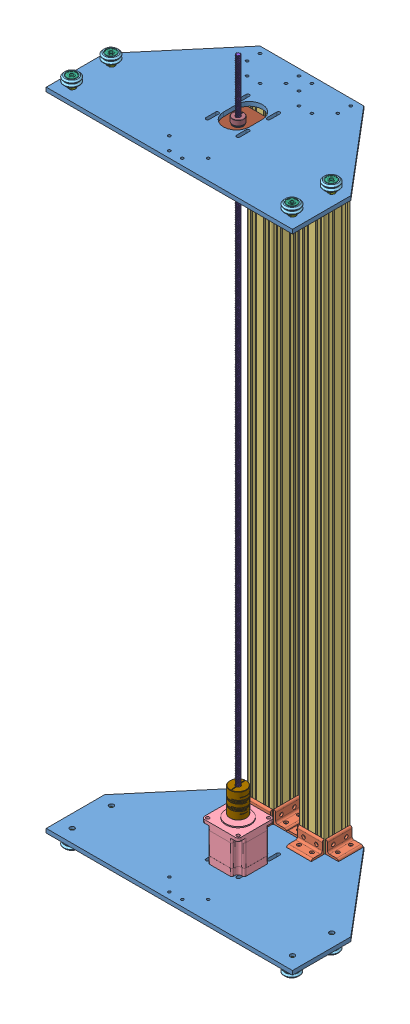
SolidWorks assembly X tray assembly, configuration Default. Lengths in mm.
Overall size (380 1106.3 220).
63 component instances, 13 part files, 91 mates.
Components (placement in the parent):
- X tray brackets-1: X tray brackets [Default] at (62.6987 262.9212 289.5469) size (380 6.35 220)
- 5537T939-1: 5537T939 [5537T939] at (202.6987 269.2712 309.5469) size (20 20 38)
- 5537T939-2: 5537T939 [5537T939] at (102.6987 269.2712 329.5469) x (0 0 1) z (-1 0 0) size (20 20 38)
- 5537T939-3: 5537T939 [5537T939] at (82.6987 269.2712 309.5469) x (-1 0 0) z (0 0 -1) size (20 20 38)
- V-Slot 40x40 Linear Rail X tray-1: V-Slot 40x40 Linear Rail X tray [Default] at (182.6987 269.2712 309.5469) x (1 0 0) z (0 1 0) size (40 40 984.25)
- V-Slot 40x40 Linear Rail X tray-2: V-Slot 40x40 Linear Rail X tray [Default] at (102.6987 269.2712 309.5469) x (1 0 0) z (0 1 0) size (40 40 984.25)
- X tray brackets-2: X tray brackets [Default] at (62.6987 1253.5212 289.5469) size (380 6.35 220)
- 5537T939-4: 5537T939 [5537T939] at (202.6987 1253.5212 309.5469) x (0 -1 0) z (0 0 1) size (20 20 38)
- 5537T939-5: 5537T939 [5537T939] at (82.6987 1253.5212 309.5469) x (-1 0 0) z (0 0 1) size (20 20 38)
- 5537T939-6: 5537T939 [5537T939] at (102.6987 1253.5212 329.5469) x (0 0 1) z (1 0 0) size (20 20 38)
- Nema 23 Stepper Motor-1: Nema 23 Stepper Motor [Default] at (142.6987 325.2712 403.4269) x (1 0 0) z (0 1 0) size (56.4 56.4 76.6)
- V wheel bearing assembly-1: V wheel bearing assembly [Default] at (298.8349 1279.1117 411.6739) x (0 -1 0) z (0 0 1) size (11 23.9 23.9)
  - Delrin V Wheel-2: Delrin V Wheel [Default] at (7.7405 13.8638 18.023) size (10.23 23.9 23.9)
  - Ball Bearing 5 x 16 x 5-2: Ball Bearing 5 x 16 x 5 [Default] at (10.7405 13.8638 18.023) size (5 16 16)
  - Ball Bearing 5 x 16 x 5-3: Ball Bearing 5 x 16 x 5 [Default] at (4.7405 13.8638 18.023) size (5 16 16)
- V wheel bearing assembly-2: V wheel bearing assembly [Default] at (298.8349 1279.1117 472.3139) x (0 -1 0) z (0 0 1) size (11 23.9 23.9)
  - Delrin V Wheel-2: Delrin V Wheel [Default] at (7.7405 13.8638 18.023) size (10.23 23.9 23.9)
  - Ball Bearing 5 x 16 x 5-2: Ball Bearing 5 x 16 x 5 [Default] at (10.7405 13.8638 18.023) size (5 16 16)
  - Ball Bearing 5 x 16 x 5-3: Ball Bearing 5 x 16 x 5 [Default] at (4.7405 13.8638 18.023) size (5 16 16)
- Eccentric Spacer 6mm-1: Eccentric Spacer 6mm [Default] at (312.6987 1259.8712 428.9069) size (11.55 8.5 10)
- Eccentric Spacer 6mm-2: Eccentric Spacer 6mm [Default] at (312.6987 1259.8712 489.5469) size (11.55 8.5 10)
- Eccentric Spacer 6mm-3: Eccentric Spacer 6mm [Default] at (-27.3013 1259.8712 428.9069) size (11.55 8.5 10)
- Eccentric Spacer 6mm-4: Eccentric Spacer 6mm [Default] at (-27.3013 1259.8712 489.5469) size (11.55 8.5 10)
- Eccentric Spacer 6mm-5: Eccentric Spacer 6mm [Default] at (-27.3013 262.9212 428.9069) x (-0.837169 0 -0.546944) z (-0.546944 0 0.837169) size (11.55 8.5 10)
- Eccentric Spacer 6mm-6: Eccentric Spacer 6mm [Default] at (-27.3013 262.9212 489.5469) x (-0.227691 0 -0.973733) z (-0.973733 0 0.227691) size (11.55 8.5 10)
- Eccentric Spacer 6mm-7: Eccentric Spacer 6mm [Default] at (312.6987 262.9212 428.9069) x (-0.311398 0 -0.95028) z (-0.95028 0 0.311398) size (11.55 8.5 10)
- Eccentric Spacer 6mm-8: Eccentric Spacer 6mm [Default] at (312.6987 262.9212 489.5469) x (-0.837169 0 -0.546944) z (-0.546944 0 0.837169) size (11.55 8.5 10)
- V wheel bearing assembly-3: V wheel bearing assembly [Default] at (-41.1651 1279.1117 411.6739) x (0 -1 0) z (0 0 1) size (11 23.9 23.9)
  - Delrin V Wheel-2: Delrin V Wheel [Default] at (7.7405 13.8638 18.023) size (10.23 23.9 23.9)
  - Ball Bearing 5 x 16 x 5-2: Ball Bearing 5 x 16 x 5 [Default] at (10.7405 13.8638 18.023) size (5 16 16)
  - Ball Bearing 5 x 16 x 5-3: Ball Bearing 5 x 16 x 5 [Default] at (4.7405 13.8638 18.023) size (5 16 16)
- V wheel bearing assembly-4: V wheel bearing assembly [Default] at (-41.1651 1279.1117 472.3139) x (0 -1 0) z (0 0 1) size (11 23.9 23.9)
  - Delrin V Wheel-2: Delrin V Wheel [Default] at (7.7405 13.8638 18.023) size (10.23 23.9 23.9)
  - Ball Bearing 5 x 16 x 5-2: Ball Bearing 5 x 16 x 5 [Default] at (10.7405 13.8638 18.023) size (5 16 16)
  - Ball Bearing 5 x 16 x 5-3: Ball Bearing 5 x 16 x 5 [Default] at (4.7405 13.8638 18.023) size (5 16 16)
- V wheel bearing assembly-5: V wheel bearing assembly [Default] at (326.1304 243.6807 472.1853) x (0 1 0) z (0 0 1) size (11 23.9 23.9)
  - Delrin V Wheel-2: Delrin V Wheel [Default] at (7.7405 13.8638 18.023) size (10.23 23.9 23.9)
  - Ball Bearing 5 x 16 x 5-2: Ball Bearing 5 x 16 x 5 [Default] at (10.7405 13.8638 18.023) size (5 16 16)
  - Ball Bearing 5 x 16 x 5-3: Ball Bearing 5 x 16 x 5 [Default] at (4.7405 13.8638 18.023) size (5 16 16)
- V wheel bearing assembly-6: V wheel bearing assembly [Default] at (325.8117 243.6807 411.1299) x (0 1 0) z (0 0 1) size (11 23.9 23.9)
  - Delrin V Wheel-2: Delrin V Wheel [Default] at (7.7405 13.8638 18.023) size (10.23 23.9 23.9)
  - Ball Bearing 5 x 16 x 5-2: Ball Bearing 5 x 16 x 5 [Default] at (10.7405 13.8638 18.023) size (5 16 16)
  - Ball Bearing 5 x 16 x 5-3: Ball Bearing 5 x 16 x 5 [Default] at (4.7405 13.8638 18.023) size (5 16 16)
- V wheel bearing assembly-7: V wheel bearing assembly [Default] at (-14.2068 243.6807 471.7038) x (0 1 0) z (0 0 1) size (11 23.9 23.9)
  - Delrin V Wheel-2: Delrin V Wheel [Default] at (7.7405 13.8638 18.023) size (10.23 23.9 23.9)
  - Ball Bearing 5 x 16 x 5-2: Ball Bearing 5 x 16 x 5 [Default] at (10.7405 13.8638 18.023) size (5 16 16)
  - Ball Bearing 5 x 16 x 5-3: Ball Bearing 5 x 16 x 5 [Default] at (4.7405 13.8638 18.023) size (5 16 16)
- V wheel bearing assembly-8: V wheel bearing assembly [Default] at (-13.8696 243.6807 411.5453) x (0 1 0) z (0 0 1) size (11 23.9 23.9)
  - Delrin V Wheel-2: Delrin V Wheel [Default] at (7.7405 13.8638 18.023) size (10.23 23.9 23.9)
  - Ball Bearing 5 x 16 x 5-2: Ball Bearing 5 x 16 x 5 [Default] at (10.7405 13.8638 18.023) size (5 16 16)
  - Ball Bearing 5 x 16 x 5-3: Ball Bearing 5 x 16 x 5 [Default] at (4.7405 13.8638 18.023) size (5 16 16)
- rod 1-4 1000 mm-1: rod 1-4 1000 mm [Défaut] at (142.6987 340.8712 403.4269) x (-0.111315 0 -0.993785) z (0.993785 0 -0.111315) size (6.95 1012.35 6.95)
- 6208K524-1: 6208K524 [6208K524] at (142.6987 349.9212 403.4269) x (-0.111315 0 -0.993785) z (0 1 0) size (25.41 25.4 38.1)
- 6138K650-1: 6138K650 [6138K65] at (142.6987 1251.4384 403.4269) x (1 0 0) z (0 -1 0) size (15.88 15.88 4.98)
- 1-4 rod bearing bracket-1: 1-4 rod bearing bracket [Default] at (142.6987 1243.9962 403.4269) size (60 9.53 60)
- 90295A441-1: 90295A441 [90295A441] at (142.6987 1253.9276 403.4269) x (0 1 0) z (-0.091752 0 -0.995782) size (1.78 11.99 11.99)
- 6435K320-2: 6435K320 [6435K32] at (142.6987 1259.6743 403.4269) x (-0.995782 0 0.091752) z (0 -1 0) size (17.46 17.48 7.98)
- 5537T939-7: 5537T939 [5537T939] at (182.6987 1253.5212 329.5469) x (0 0 1) z (1 0 0) size (20 20 38)
- 5537T939-8: 5537T939 [5537T939] at (182.6987 269.2712 329.5469) x (0 0 1) z (-1 0 0) size (20 20 38)
- 5537T939-9: 5537T939 [5537T939] at (162.6987 1253.5212 309.5469) x (-1 0 0) z (0 0 1) size (20 20 38)
- 5537T939-10: 5537T939 [5537T939] at (122.6987 1253.5212 309.5469) x (0 -1 0) z (0 0 1) size (20 20 38)
- 5537T939-11: 5537T939 [5537T939] at (122.6987 269.2712 309.5469) size (20 20 38)
- 5537T939-12: 5537T939 [5537T939] at (162.6987 269.2712 309.5469) x (-1 0 0) z (0 0 -1) size (20 20 38)
Mates (geometry in assembly coordinates):
- Coincident1: coincident anti-aligned: plane of X tray brackets-1 through (62.6987 269.2712 289.5469) normal (0 1 0); plane of 5537T939-1 through (222.6987 269.2712 328.5469) normal (0 -1 0)
- Coincident2: coincident anti-aligned: plane of X tray brackets-1 through (62.6987 269.2712 289.5469) normal (0 1 0); plane of 5537T939-2 through (83.6987 269.2712 349.5469) normal (0 -1 0)
- Coincident3: coincident anti-aligned: plane of X tray brackets-1 through (62.6987 269.2712 289.5469) normal (0 1 0); plane of 5537T939-3 through (62.6987 269.2712 290.5469) normal (0 -1 0)
- Coincident4: coincident anti-aligned: plane of X tray brackets-1 through (62.6987 269.2712 289.5469) normal (0 1 0); plane of V-Slot 40x40 Linear Rail X tray-1 through (182.6987 269.2712 309.5469) normal (0 -1 0)
- Coincident5: coincident aligned: plane of X tray brackets-1 through (62.6987 269.2712 289.5469) normal (0 0 -1); plane of V-Slot 40x40 Linear Rail X tray-1 through (182.6987 1253.5212 289.5469) normal (0 0 -1)
- Coincident6: coincident anti-aligned: plane of X tray brackets-1 through (62.6987 269.2712 289.5469) normal (0 1 0); plane of V-Slot 40x40 Linear Rail X tray-2 through (102.6987 269.2712 309.5469) normal (0 -1 0)
- Coincident7: coincident aligned: plane of X tray brackets-1 through (62.6987 269.2712 289.5469) normal (0 0 -1); plane of V-Slot 40x40 Linear Rail X tray-2 through (102.6987 1253.5212 289.5469) normal (0 0 -1)
- Coincident9: coincident anti-aligned: plane of 5537T939-2 through (83.6987 269.2712 329.5469) normal (0 0 -1); plane of V-Slot 40x40 Linear Rail X tray-1 through (182.6987 1253.5212 329.5469) normal (0 0 1)
- Coincident10: coincident anti-aligned: plane of 5537T939-1 through (202.6987 269.2712 328.5469) normal (-1 0 0); plane of V-Slot 40x40 Linear Rail X tray-1 through (202.6987 1253.5212 309.5469) normal (1 0 0)
- Coincident11: coincident anti-aligned: plane of 5537T939-3 through (82.6987 269.2712 290.5469) normal (1 0 0); plane of V-Slot 40x40 Linear Rail X tray-2 through (82.6987 1253.5212 309.5469) normal (-1 0 0)
- Coincident15: coincident anti-aligned: plane of V-Slot 40x40 Linear Rail X tray-2 through (102.6987 1253.5212 309.5469) normal (0 1 0); plane of X tray brackets-2 through (62.6987 1253.5212 289.5469) normal (0 -1 0)
- Coincident16: coincident aligned: plane of V-Slot 40x40 Linear Rail X tray-2 through (102.6987 1253.5212 289.5469) normal (0 0 -1); plane of X tray brackets-2 through (62.6987 1259.8712 289.5469) normal (0 0 -1)
- Coincident17: coincident anti-aligned: plane of X tray brackets-2 through (62.6987 1253.5212 289.5469) normal (0 -1 0); plane of 5537T939-5 through (62.6987 1253.5212 328.5469) normal (0 1 0)
- Coincident18: coincident anti-aligned: plane of V-Slot 40x40 Linear Rail X tray-2 through (82.6987 1253.5212 309.5469) normal (-1 0 0); plane of 5537T939-5 through (82.6987 1253.5212 328.5469) normal (1 0 0)
- Coincident19: coincident anti-aligned: plane of V-Slot 40x40 Linear Rail X tray-1 through (202.6987 1253.5212 309.5469) normal (1 0 0); plane of 5537T939-4 through (202.6987 1233.5212 328.5469) normal (-1 0 0)
- Coincident20: coincident anti-aligned: plane of X tray brackets-2 through (62.6987 1253.5212 289.5469) normal (0 -1 0); plane of 5537T939-4 through (202.6987 1253.5212 328.5469) normal (0 1 0)
- Coincident21: coincident anti-aligned: plane of X tray brackets-2 through (62.6987 1253.5212 289.5469) normal (0 -1 0); plane of 5537T939-6 through (121.6987 1253.5212 349.5469) normal (0 1 0)
- Coincident22: coincident anti-aligned: plane of V-Slot 40x40 Linear Rail X tray-2 through (102.6987 1253.5212 329.5469) normal (0 0 1); plane of 5537T939-6 through (121.6987 1253.5212 329.5469) normal (0 0 -1)
- Concentric1: concentric aligned: circle of 5537T939-3; cylinder of X tray brackets-1 through (72.6987 269.2712 299.5469) axis (0 1 0) radius 2.1
- Concentric2: concentric aligned: circle of 5537T939-1; cylinder of X tray brackets-1 through (212.6987 269.2712 299.5469) axis (0 1 0) radius 2.1
- Concentric3: concentric aligned: circle of 5537T939-2; cylinder of X tray brackets-1 through (92.6987 269.2712 339.5469) axis (0 1 0) radius 2.1
- Concentric4: concentric anti-aligned: circle of 5537T939-5; cylinder of X tray brackets-2 through (72.6987 1259.8712 299.5469) axis (0 1 0) radius 2.1
- Concentric5: concentric anti-aligned: circle of 5537T939-6; cylinder of X tray brackets-2 through (92.6987 1259.8712 339.5469) axis (0 1 0) radius 2.1
- Concentric6: concentric anti-aligned: circle of 5537T939-4; cylinder of X tray brackets-2 through (212.6987 1259.8712 319.5469) axis (0 1 0) radius 2.1
- Coincident24: coincident anti-aligned: plane of X tray brackets-1 through (62.6987 269.2712 289.5469) normal (0 1 0); plane of Nema 23 Stepper Motor-1 through (158.7687 269.2712 377.7269) normal (0 -1 0)
- Slot1: slot aligned: cylinder of Nema 23 Stepper Motor-1 through (119.1287 269.2701 379.8569) axis (0 1 0) radius 2.55; plane of X tray brackets-1 through (121.6787 262.9212 379.8569) normal (-1 0 0); cylinder of X tray brackets-1 through (119.1287 269.2712 364.9569) axis (0 1 0) radius 2.55
- Slot2: slot aligned: cylinder of X tray brackets-1 through (166.2687 269.2712 364.9569) axis (0 1 0) radius 2.55; cylinder of Nema 23 Stepper Motor-1 through (166.2687 269.2701 379.8569) axis (0 1 0) radius 2.55; cylinder of X tray brackets-1 through (166.2687 269.2712 379.8569) axis (0 1 0) radius 2.55
- Concentric11: concentric anti-aligned: cylinder of X tray brackets-1 through (-27.3013 269.2712 489.5469) axis (0 1 0) radius 3.55; cylinder of Eccentric Spacer 6mm-6 through (-27.3013 265.4212 489.5469) axis (0 -1 0) radius 3.555
- Coincident30: coincident anti-aligned: plane of X tray brackets-1 through (62.6987 262.9212 289.5469) normal (0 -1 0); plane of Eccentric Spacer 6mm-6 through (-27.3013 262.9212 489.5469) normal (0 1 0)
- Concentric12: concentric anti-aligned: cylinder of X tray brackets-1 through (-27.3013 269.2712 428.9069) axis (0 1 0) radius 3.55; cylinder of Eccentric Spacer 6mm-5 through (-27.3013 265.4212 428.9069) axis (0 -1 0) radius 3.555
- Coincident31: coincident anti-aligned: plane of X tray brackets-1 through (62.6987 262.9212 289.5469) normal (0 -1 0); plane of Eccentric Spacer 6mm-5 through (-27.3013 262.9212 428.9069) normal (0 1 0)
- Concentric13: concentric anti-aligned: cylinder of X tray brackets-1 through (312.6987 269.2712 428.9069) axis (0 1 0) radius 3.55; cylinder of Eccentric Spacer 6mm-7 through (312.6987 265.4212 428.9069) axis (0 -1 0) radius 3.555
- Coincident32: coincident anti-aligned: plane of X tray brackets-1 through (62.6987 262.9212 289.5469) normal (0 -1 0); plane of Eccentric Spacer 6mm-7 through (312.6987 262.9212 428.9069) normal (0 1 0)
- Concentric14: concentric anti-aligned: cylinder of X tray brackets-1 through (312.6987 269.2712 489.5469) axis (0 1 0) radius 3.55; cylinder of Eccentric Spacer 6mm-8 through (312.6987 265.4212 489.5469) axis (0 -1 0) radius 3.555
- Coincident33: coincident anti-aligned: plane of X tray brackets-1 through (62.6987 262.9212 289.5469) normal (0 -1 0); plane of Eccentric Spacer 6mm-8 through (312.6987 262.9212 489.5469) normal (0 1 0)
- Concentric15: concentric aligned: cylinder of X tray brackets-2 through (312.6987 1259.8712 428.9069) axis (0 1 0) radius 3.55; cylinder of Eccentric Spacer 6mm-1 through (312.6987 1257.3712 428.9069) axis (0 1 0) radius 3.555
- Coincident34: coincident anti-aligned: plane of X tray brackets-2 through (62.6987 1259.8712 289.5469) normal (0 1 0); plane of Eccentric Spacer 6mm-1 through (312.6987 1259.8712 428.9069) normal (0 -1 0)
- Concentric16: concentric aligned: cylinder of X tray brackets-2 through (312.6987 1259.8712 489.5469) axis (0 1 0) radius 3.55; cylinder of Eccentric Spacer 6mm-2 through (312.6987 1257.3712 489.5469) axis (0 1 0) radius 3.555
- Coincident35: coincident anti-aligned: plane of X tray brackets-2 through (62.6987 1259.8712 289.5469) normal (0 1 0); plane of Eccentric Spacer 6mm-2 through (312.6987 1259.8712 489.5469) normal (0 -1 0)
- Concentric17: concentric aligned: cylinder of X tray brackets-2 through (-27.3013 1259.8712 489.5469) axis (0 1 0) radius 3.55; cylinder of Eccentric Spacer 6mm-4 through (-27.3013 1257.3712 489.5469) axis (0 1 0) radius 3.555
- Coincident36: coincident anti-aligned: plane of X tray brackets-2 through (62.6987 1259.8712 289.5469) normal (0 1 0); plane of Eccentric Spacer 6mm-4 through (-27.3013 1259.8712 489.5469) normal (0 -1 0)
- Concentric18: concentric aligned: cylinder of X tray brackets-2 through (-27.3013 1259.8712 428.9069) axis (0 1 0) radius 3.55; cylinder of Eccentric Spacer 6mm-3 through (-27.3013 1257.3712 428.9069) axis (0 1 0) radius 3.555
- Coincident37: coincident anti-aligned: plane of X tray brackets-2 through (62.6987 1259.8712 289.5469) normal (0 1 0); plane of Eccentric Spacer 6mm-3 through (-27.3013 1259.8712 428.9069) normal (0 -1 0)
- Concentric19: concentric anti-aligned: cylinder of V wheel bearing assembly-1/Ball Bearing 5 x 16 x 5-2 through (312.6987 1268.3712 429.6969) axis (0 -1 0) radius 2.5; cylinder of Eccentric Spacer 6mm-1 through (312.6987 1257.3712 429.6969) axis (0 1 0) radius 2.5
- Coincident38: coincident anti-aligned: plane of V wheel bearing assembly-1/Ball Bearing 5 x 16 x 5-2 through (315.1987 1265.8712 429.6969) normal (0 -1 0); plane of Eccentric Spacer 6mm-1 through (312.6987 1265.8712 428.9069) normal (0 1 0)
- Concentric20: concentric anti-aligned: cylinder of V wheel bearing assembly-2/Ball Bearing 5 x 16 x 5-2 through (312.6987 1268.3712 490.3369) axis (0 -1 0) radius 2.5; cylinder of Eccentric Spacer 6mm-2 through (312.6987 1257.3712 490.3369) axis (0 1 0) radius 2.5
- Coincident39: coincident anti-aligned: plane of V wheel bearing assembly-2/Ball Bearing 5 x 16 x 5-2 through (315.1987 1265.8712 490.3369) normal (0 -1 0); plane of Eccentric Spacer 6mm-2 through (312.6987 1265.8712 489.5469) normal (0 1 0)
- Concentric21: concentric anti-aligned: cylinder of Eccentric Spacer 6mm-4 through (-27.3013 1257.3712 490.3369) axis (0 1 0) radius 2.5; cylinder of V wheel bearing assembly-4/Ball Bearing 5 x 16 x 5-2 through (-27.3013 1268.3712 490.3369) axis (0 -1 0) radius 2.5
- Coincident40: coincident anti-aligned: plane of Eccentric Spacer 6mm-4 through (-27.3013 1265.8712 489.5469) normal (0 1 0); plane of V wheel bearing assembly-4/Ball Bearing 5 x 16 x 5-2 through (-24.8013 1265.8712 490.3369) normal (0 -1 0)
- Concentric22: concentric anti-aligned: cylinder of Eccentric Spacer 6mm-3 through (-27.3013 1257.3712 429.6969) axis (0 1 0) radius 2.5; cylinder of V wheel bearing assembly-3/Ball Bearing 5 x 16 x 5-2 through (-27.3013 1268.3712 429.6969) axis (0 -1 0) radius 2.5
- Coincident41: coincident anti-aligned: plane of Eccentric Spacer 6mm-3 through (-27.3013 1265.8712 428.9069) normal (0 1 0); plane of V wheel bearing assembly-3/Ball Bearing 5 x 16 x 5-2 through (-24.8013 1265.8712 429.6969) normal (0 -1 0)
- Concentric23: concentric anti-aligned: cylinder of Eccentric Spacer 6mm-7 through (311.9479 265.4212 429.1529) axis (0 -1 0) radius 2.5; cylinder of V wheel bearing assembly-6/Ball Bearing 5 x 16 x 5-2 through (311.9479 254.4212 429.1529) axis (0 1 0) radius 2.5
- Coincident42: coincident anti-aligned: plane of Eccentric Spacer 6mm-7 through (312.6987 256.9212 428.9069) normal (0 -1 0); plane of V wheel bearing assembly-6/Ball Bearing 5 x 16 x 5-2 through (309.4479 256.9212 429.1529) normal (0 1 0)
- Concentric24: concentric anti-aligned: cylinder of Eccentric Spacer 6mm-8 through (312.2666 265.4212 490.2083) axis (0 -1 0) radius 2.5; cylinder of V wheel bearing assembly-5/Ball Bearing 5 x 16 x 5-2 through (312.2666 254.4212 490.2083) axis (0 1 0) radius 2.5
- Coincident43: coincident anti-aligned: plane of Eccentric Spacer 6mm-8 through (312.6987 256.9212 489.5469) normal (0 -1 0); plane of V wheel bearing assembly-5/Ball Bearing 5 x 16 x 5-2 through (309.7666 256.9212 490.2083) normal (0 1 0)
- Concentric25: concentric anti-aligned: cylinder of Eccentric Spacer 6mm-5 through (-27.7334 265.4212 429.5683) axis (0 -1 0) radius 2.5; cylinder of V wheel bearing assembly-8/Ball Bearing 5 x 16 x 5-2 through (-27.7334 254.4212 429.5683) axis (0 1 0) radius 2.5
- Coincident44: coincident anti-aligned: plane of Eccentric Spacer 6mm-5 through (-27.3013 256.9212 428.9069) normal (0 -1 0); plane of V wheel bearing assembly-8/Ball Bearing 5 x 16 x 5-2 through (-30.2334 256.9212 429.5683) normal (0 1 0)
- Concentric26: concentric anti-aligned: cylinder of Eccentric Spacer 6mm-6 through (-28.0706 265.4212 489.7268) axis (0 -1 0) radius 2.5; cylinder of V wheel bearing assembly-7/Ball Bearing 5 x 16 x 5-2 through (-28.0706 254.4212 489.7268) axis (0 1 0) radius 2.5
- Coincident45: coincident anti-aligned: plane of Eccentric Spacer 6mm-6 through (-27.3013 256.9212 489.5469) normal (0 -1 0); plane of V wheel bearing assembly-7/Ball Bearing 5 x 16 x 5-2 through (-30.5706 256.9212 489.7268) normal (0 1 0)
- Coincident46: coincident anti-aligned: plane of Nema 23 Stepper Motor-1 through (142.6987 345.8712 403.4269) normal (0 1 0); plane of rod 1-4 1000 mm-1 through (142.6987 345.8712 403.4269) normal (0 -1 0)
- Concentric27: concentric anti-aligned: cylinder of Nema 23 Stepper Motor-1 through (142.6987 345.8712 403.4269) axis (0 -1 0) radius 3.175; cylinder of 6208K524-1 through (142.6987 330.8712 403.4269) axis (0 1 0) radius 3.175
- Coincident47: coincident anti-aligned: plane of Nema 23 Stepper Motor-1 through (142.6987 330.8712 403.4269) normal (0 1 0); plane of 6208K524-1 through (142.6987 330.8712 403.4269) normal (0 -1 0)
- Concentric28: concentric aligned: cylinder of rod 1-4 1000 mm-1 through (142.6987 1350.8712 403.4269) axis (0 -1 0) radius 2.3375; cylinder of 6208K524-1 through (142.6987 368.9712 403.4269) axis (0 -1 0) radius 3.175
- Coincident48: coincident anti-aligned: plane of X tray brackets-2 through (62.6987 1253.5212 289.5469) normal (0 -1 0); plane of 1-4 rod bearing bracket-1 through (142.6987 1253.5212 403.4269) normal (0 1 0)
- Slot4: slot aligned: cylinder of 1-4 rod bearing bracket-1 through (119.1287 1253.5212 379.8569) axis (0 1 0) radius 2.65; cylinder of X tray brackets-2 through (119.1287 1259.8712 364.9569) axis (0 1 0) radius 2.55; cylinder of X tray brackets-2 through (119.1287 1259.8712 379.8569) axis (0 1 0) radius 2.55
- Slot3: slot aligned: cylinder of 1-4 rod bearing bracket-1 through (166.2687 1253.5212 426.9969) axis (0 1 0) radius 2.65; cylinder of X tray brackets-2 through (166.2687 1259.8712 412.0969) axis (0 1 0) radius 2.55; cylinder of X tray brackets-2 through (166.2687 1259.8712 426.9969) axis (0 1 0) radius 2.55
- Concentric31: concentric anti-aligned: cylinder of 6138K650-1 through (142.6987 1248.9492 403.4269) axis (0 -1 0) radius 3.175; cylinder of 1-4 rod bearing bracket-1 through (142.6987 1243.9962 403.4269) axis (0 1 0) radius 6.35
- Coincident49: coincident anti-aligned: plane of 6138K650-1 through (142.6987 1248.9492 411.1155) normal (0 -1 0); plane of 1-4 rod bearing bracket-1 through (142.6987 1248.9492 403.4269) normal (0 1 0)
- Coincident52: coincident anti-aligned: plane of 6138K650-1 through (142.6987 1253.9276 406.8508) normal (0 1 0); plane of 90295A441-1 through (142.6987 1253.9276 403.4269) normal (0 -1 0)
- Concentric34: concentric aligned: cylinder of rod 1-4 1000 mm-1 through (142.6987 1350.8712 403.4269) axis (0 -1 0) radius 2.3375; cylinder of 90295A441-1 through (142.6987 1255.7056 403.4269) axis (0 -1 0) radius 3.2004
- Concentric35: concentric anti-aligned: cylinder of rod 1-4 1000 mm-1 through (142.6987 1350.8712 403.4269) axis (0 -1 0) radius 2.3375; cylinder of 6435K320-2 through (142.6987 1255.7056 403.4269) axis (0 1 0) radius 3.175
- Coincident53: coincident anti-aligned: plane of 90295A441-1 through (142.6987 1255.7056 403.4269) normal (0 1 0); plane of 6435K320-2 through (142.6987 1255.7056 403.4269) normal (0 -1 0)
- Coincident54: coincident anti-aligned: plane of X tray brackets-2 through (62.6987 1253.5212 289.5469) normal (0 -1 0); plane of 5537T939-7 through (201.6987 1253.5212 349.5469) normal (0 1 0)
- Coincident55: coincident anti-aligned: plane of V-Slot 40x40 Linear Rail X tray-1 through (182.6987 1253.5212 329.5469) normal (0 0 1); plane of 5537T939-7 through (201.6987 1253.5212 329.5469) normal (0 0 -1)
- Concentric36: concentric aligned: cylinder of X tray brackets-2 through (172.6987 1259.8712 339.5469) axis (0 1 0) radius 2.1; cylinder of 5537T939-7 through (172.6987 1233.5212 339.5469) axis (0 1 0) radius 2.75
- Coincident56: coincident anti-aligned: plane of X tray brackets-1 through (62.6987 269.2712 289.5469) normal (0 1 0); plane of 5537T939-8 through (163.6987 269.2712 349.5469) normal (0 -1 0)
- Concentric37: concentric anti-aligned: cylinder of 5537T939-8 through (192.6987 289.2712 339.5469) axis (0 -1 0) radius 2.75; cylinder of X tray brackets-1 through (192.6987 269.2712 339.5469) axis (0 1 0) radius 2.1
- Coincident58: coincident anti-aligned: plane of V-Slot 40x40 Linear Rail X tray-1 through (182.6987 1253.5212 329.5469) normal (0 0 1); plane of 5537T939-8 through (163.6987 269.2712 329.5469) normal (0 0 -1)
- Concentric38: concentric aligned: circle of rod 1-4 1000 mm-1; cylinder of 1-4 rod bearing bracket-1 through (142.6987 1243.9962 403.4269) axis (0 1 0) radius 6.35
- Coincident59: coincident anti-aligned: plane of X tray brackets-1 through (62.6987 269.2712 289.5469) normal (0 1 0); plane of 5537T939-12 through (142.6987 269.2712 290.5469) normal (0 -1 0)
- Coincident60: coincident anti-aligned: plane of X tray brackets-1 through (62.6987 269.2712 289.5469) normal (0 1 0); plane of 5537T939-11 through (142.6987 269.2712 328.5469) normal (0 -1 0)
- Coincident61: coincident anti-aligned: plane of V-Slot 40x40 Linear Rail X tray-1 through (162.6987 1253.5212 309.5469) normal (-1 0 0); plane of 5537T939-12 through (162.6987 269.2712 290.5469) normal (1 0 0)
- Coincident62: coincident anti-aligned: plane of V-Slot 40x40 Linear Rail X tray-2 through (122.6987 1253.5212 309.5469) normal (1 0 0); plane of 5537T939-11 through (122.6987 269.2712 328.5469) normal (-1 0 0)
- Concentric39: concentric anti-aligned: cylinder of X tray brackets-1 through (132.6987 269.2712 299.5469) axis (0 1 0) radius 2.1; cylinder of 5537T939-11 through (132.6987 289.2712 299.5469) axis (0 -1 0) radius 2.75
- Concentric40: concentric anti-aligned: cylinder of X tray brackets-1 through (152.6987 269.2712 299.5469) axis (0 1 0) radius 2.1; cylinder of 5537T939-12 through (152.6987 289.2712 299.5469) axis (0 -1 0) radius 2.75
- Coincident63: coincident anti-aligned: plane of X tray brackets-2 through (62.6987 1253.5212 289.5469) normal (0 -1 0); plane of 5537T939-9 through (142.6987 1253.5212 328.5469) normal (0 1 0)
- Coincident64: coincident anti-aligned: plane of X tray brackets-2 through (62.6987 1253.5212 289.5469) normal (0 -1 0); plane of 5537T939-10 through (122.6987 1253.5212 328.5469) normal (0 1 0)
- Coincident65: coincident anti-aligned: plane of V-Slot 40x40 Linear Rail X tray-1 through (162.6987 1253.5212 309.5469) normal (-1 0 0); plane of 5537T939-9 through (162.6987 1253.5212 328.5469) normal (1 0 0)
- Coincident66: coincident anti-aligned: plane of V-Slot 40x40 Linear Rail X tray-2 through (122.6987 1253.5212 309.5469) normal (1 0 0); plane of 5537T939-10 through (122.6987 1233.5212 328.5469) normal (-1 0 0)
- Concentric41: concentric aligned: cylinder of X tray brackets-2 through (132.6987 1259.8712 299.5469) axis (0 1 0) radius 2.1; cylinder of 5537T939-10 through (132.6987 1233.5212 299.5469) axis (0 1 0) radius 2.75
- Concentric42: concentric aligned: cylinder of X tray brackets-2 through (152.6987 1259.8712 299.5469) axis (0 1 0) radius 2.1; cylinder of 5537T939-9 through (152.6987 1233.5212 299.5469) axis (0 1 0) radius 2.75
